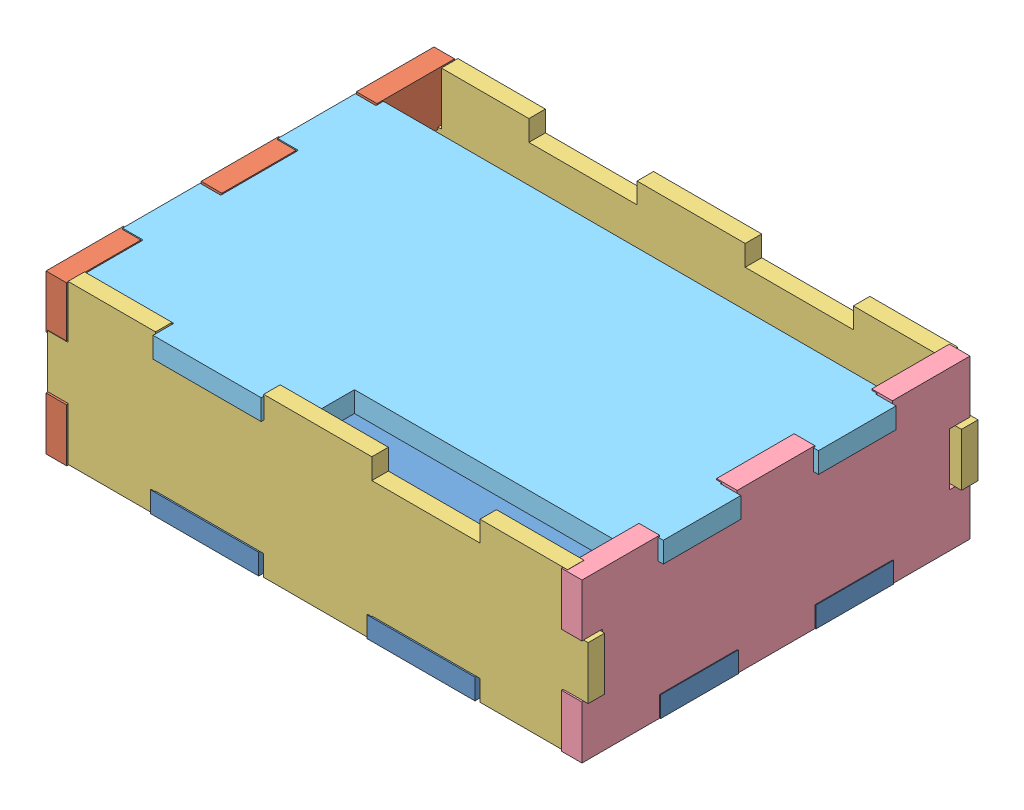
SolidWorks assembly Assem1, configuration Default. Lengths in mm.
Overall size (84.11 24.76 60.21).
6 component instances, 5 part files, 0 mates.
Components (placement in the parent):
- bottom face-1: bottom face [Default] at (27.2186 36.7406 69.3267) size (83.18 3.17 59.69)
- front face(ports)-1: front face(ports) [Default] at (-10.8187 48.658 69.1448) x (0 0 -1) z (0 1 0) size (59.69 3.17 24.38)
- sides-1: sides [Default] at (27.8777 49.0327 96.5173) x (0 1 0) z (1 0 0) size (24.38 2.54 83.18)
- back face-1: back face [Default] at (68.7626 49.0089 69.4476) x (0 0 1) z (0 -1 0) size (59.69 3.17 24.38)
- sides-2: sides [Default] at (28.1406 48.9955 39.3447) x (0 1 0) z (1 0 0) size (24.38 2.54 83.18)
- top face(pins)-1: top face(pins) [Default] at (27.9492 57.8505 69.6624) size (83.18 3.17 59.69)
